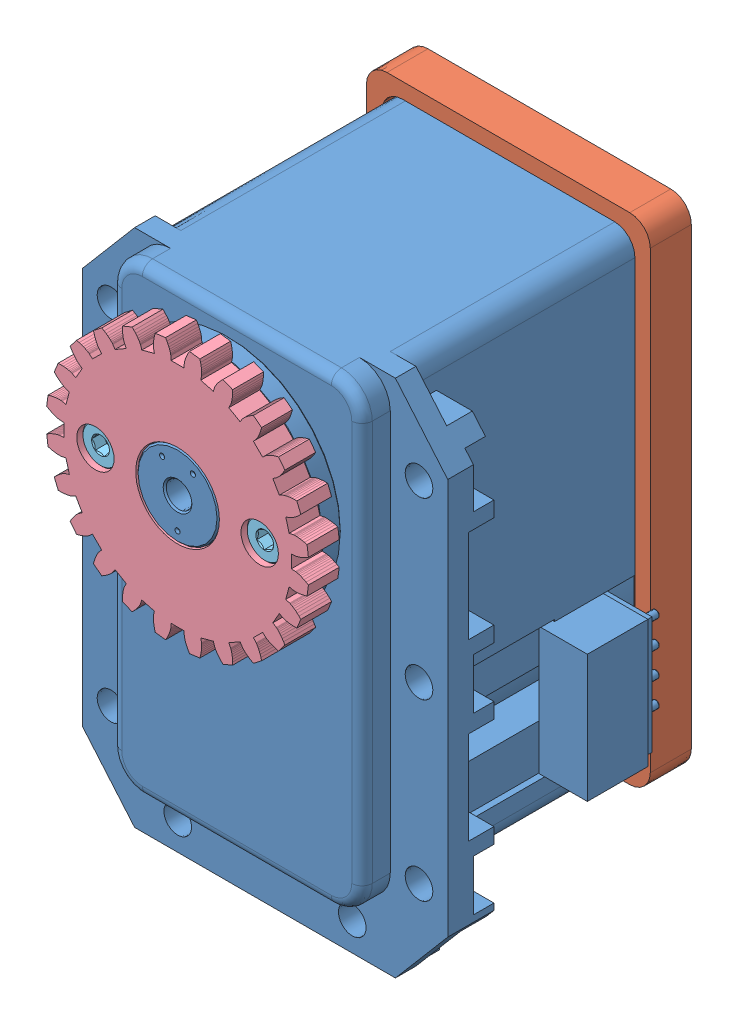
SolidWorks assembly block_actuator_gear_o, configuration Default. Lengths in mm.
Overall size (35.6 52.23 39.77).
9 component instances, 5 part files, 18 mates.
Components (placement in the parent):
- dynamixel MX-28-exposed-1: dynamixel MX-28-exposed [Back Off] at origin size (35.6 50.6 39.77)
- d2_o-1: d2_o [Default] at (-12.375 -33.125 -8.75) x (0 1 0) z (0 0 -1) size (48.25 27.65 4)
- 91772A266 2-56 L5-4 pan-1: 91772A266 2-56 L5-4 pan [91772A266] at (-9.3 9 12.65) x (-0.205276 0.978704 0) z (0 0 -1) size (4.24 4.24 27.06)
- 91772A266 2-56 L5-4 pan-2: 91772A266 2-56 L5-4 pan [91772A266] at (9.2 9 12.65) x (-0.795891 0.60544 0) z (0 0 -1) size (4.24 4.24 27.06)
- 91772A266 2-56 L5-4 pan-3: 91772A266 2-56 L5-4 pan [91772A266] at (9.2 -30 12.65) x (-0.25415 0.967165 0) z (0 0 -1) size (4.24 4.24 27.06)
- 91772A266 2-56 L5-4 pan-4: 91772A266 2-56 L5-4 pan [91772A266] at (-9.3 -30 12.65) x (-0.098208 -0.995166 0) z (0 0 -1) size (4.24 4.24 27.06)
- b2_o-1: b2_o [Default] at (0 0 20.52) size (25.49 25.49 3)
- 91292A003 M2 L3 socket-1: 91292A003 M2 L3 socket [91292A003] at (-8 0 18.02) x (-0.923728 -0.383049 0) z (0 0 -1) size (3.8 3.8 5.09)
- 91292A003 M2 L3 socket-2: 91292A003 M2 L3 socket [91292A003] at (8 0 18.02) x (-0.577343 -0.816502 0) z (0 0 -1) size (3.8 3.8 5.09)
Mates (geometry in assembly coordinates):
- Concentric2: concentric: cylinder of dynamixel MX-28-exposed-1 through (9.2 9 1.25) axis (0 0 -1) radius 1.15; cylinder of d2_o-1 through (9.2 9 -13.1906) axis (0 0 1) radius 1.075
- Parallel1: parallel: plane of dynamixel MX-28-exposed-1 through (12.2 12 -17.75) normal (0 1 0); plane of d2_o-1 through (-13.875 13.625 -12.75) normal (0 1 0)
- Coincident2: coincident: plane of dynamixel MX-28-exposed-1 through (-10.2 -31 -8.75) normal (0 0 -1); plane of d2_o-1 through (-12.375 -33.125 -8.75) normal (0 0 1)
- Concentric4: concentric: cylinder of d2_o-1 through (-9.3 9 -13.1906) axis (0 0 1) radius 1.075; circle of 91772A266 2-56 L5-4 pan-1
- Coincident3: coincident: plane of d2_o-1 through (-12.375 -33.125 -12.75) normal (0 0 -1); plane of 91772A266 2-56 L5-4 pan-1 through (-9.3 9 -12.75) normal (0 0 1)
- Concentric5: concentric: cylinder of d2_o-1 through (9.2 9 -13.1906) axis (0 0 1) radius 1.075; circle of 91772A266 2-56 L5-4 pan-2
- Coincident4: coincident: plane of d2_o-1 through (-12.375 -33.125 -12.75) normal (0 0 -1); plane of 91772A266 2-56 L5-4 pan-2 through (9.2 9 -12.75) normal (0 0 1)
- Concentric6: concentric: cylinder of d2_o-1 through (9.2 -30 -13.1906) axis (0 0 1) radius 1.075; circle of 91772A266 2-56 L5-4 pan-3
- Coincident5: coincident: plane of d2_o-1 through (-12.375 -33.125 -12.75) normal (0 0 -1); circle of 91772A266 2-56 L5-4 pan-3
- Concentric7: concentric: cylinder of d2_o-1 through (-9.3 -30 -13.1906) axis (0 0 1) radius 1.075; circle of 91772A266 2-56 L5-4 pan-4
- Coincident6: coincident: plane of d2_o-1 through (-12.375 -33.125 -12.75) normal (0 0 -1); plane of 91772A266 2-56 L5-4 pan-4 through (-9.3 -30 -12.75) normal (0 0 1)
- Concentric13: concentric: cylinder of dynamixel MX-28-exposed-1 through (0 0 37.8337) axis (0 0 -1) radius 4; cylinder of b2_o-1 through (0 0 20.52) axis (0 0 1) radius 4.075
- Coincident11: coincident: plane of dynamixel MX-28-exposed-1 through (0 0 20.52) normal (0 0 1); plane of b2_o-1 through (0 0 20.52) normal (0 0 -1)
- Concentric14: concentric: cylinder of dynamixel MX-28-exposed-1 through (-8 0 -19.251) axis (0 0 1) radius 0.9; cylinder of b2_o-1 through (-8 0 21.02) axis (0 0 1) radius 1.825
- Concentric15: concentric: cylinder of b2_o-1 through (-8 0 21.02) axis (0 0 1) radius 1.825; cylinder of 91292A003 M2 L3 socket-1 through (-8 0 23.02) axis (0 0 -1) radius 1.9
- Coincident12: coincident: plane of b2_o-1 through (-8 0 21.02) normal (0 0 1); plane of 91292A003 M2 L3 socket-1 through (-8 0 21.02) normal (0 0 -1)
- Concentric16: concentric: cylinder of b2_o-1 through (8 0 21.02) axis (0 0 1) radius 1.825; cylinder of 91292A003 M2 L3 socket-2 through (8 0 23.02) axis (0 0 -1) radius 1.9
- Coincident13: coincident: plane of b2_o-1 through (8 0 21.02) normal (0 0 1); plane of 91292A003 M2 L3 socket-2 through (8 0 21.02) normal (0 0 -1)
